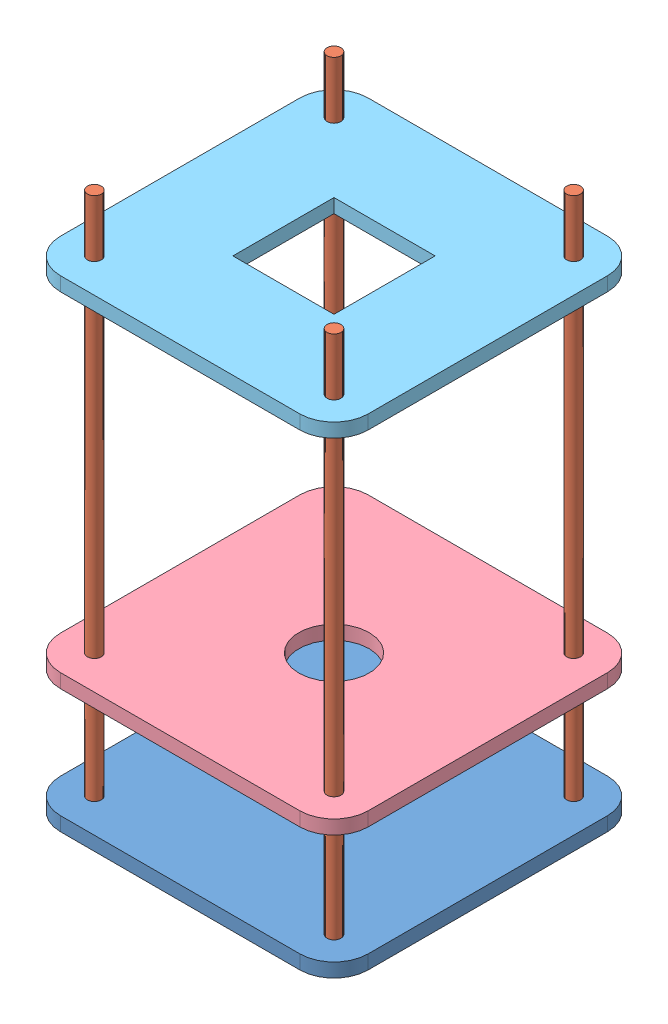
SolidWorks assembly ensanbblaje, configuration Predeterminado. Lengths in mm.
Overall size (280 500 280).
11 component instances, 5 part files, 16 mates.
Components (placement in the parent):
- base-2: base [Predeterminado] at (-174.1135 -97.9737 225.0155) size (280 12.7 280)
- VARILLA-2: VARILLA [Predeterminado] at (-283.1135 -107.9737 334.0155) x (0.715876 0 -0.698227) z (0.698227 0 0.715876) size (12.7 500 12.7)
- VARILLA-3: VARILLA [Predeterminado] at (-283.1135 -107.9737 116.0155) size (12.7 500 12.7)
- VARILLA-4: VARILLA [Predeterminado] at (-65.1135 -107.9737 334.0155) size (12.7 500 12.7)
- VARILLA-5: VARILLA [Predeterminado] at (-65.1135 -107.9737 116.0155) size (12.7 500 12.7)
- tuerca-1: tuerca [Predeterminado] at (-65.1135 -107.9737 116.0155) size (32.26 10 25.4)
- tuerca-2: tuerca [Predeterminado] at (-283.1135 -107.9737 334.0155) size (32.26 10 25.4)
- tuerca-3: tuerca [Predeterminado] at (-283.1135 -107.9737 116.0155) size (32.26 10 25.4)
- tuerca-4: tuerca [Predeterminado] at (-65.1135 -107.9737 334.0155) size (32.26 10 25.4)
- medio-1: medio [Predeterminado] at (-174.1135 14.7263 225.0155) size (280 12.7 280)
- tetcho-1: tetcho [Predeterminado] at (-174.1135 327.4263 225.0155) size (280 12.7 280)
Mates (geometry in assembly coordinates):
- Concéntrica1: concentric: cylinder of base-2 through (-283.1135 -97.9737 334.0155) axis (0 1 0) radius 6.35; cylinder of VARILLA-2 through (-283.1135 392.0263 334.0155) axis (0 -1 0) radius 6.35
- Concéntrica2: concentric: cylinder of base-2 through (-65.1135 -97.9737 334.0155) axis (0 1 0) radius 6.35; cylinder of VARILLA-4 through (-65.1135 392.0263 334.0155) axis (0 -1 0) radius 6.35
- Concéntrica3: concentric: cylinder of base-2 through (-283.1135 -97.9737 116.0155) axis (0 1 0) radius 6.35; cylinder of VARILLA-3 through (-283.1135 392.0263 116.0155) axis (0 -1 0) radius 6.35
- Coincidente3: coincident: circle of VARILLA-3; circle of tuerca-3
- Coincidente4: coincident: plane of base-2 through (-283.1135 -97.9737 334.0155) normal (0 -1 0); plane of tuerca-3 through (-283.1135 -97.9737 116.0155) normal (0 1 0)
- Coincidente5: coincident: circle of VARILLA-5; circle of tuerca-1
- Coincidente6: coincident: plane of base-2 through (-283.1135 -97.9737 334.0155) normal (0 -1 0); plane of tuerca-1 through (-65.1135 -97.9737 116.0155) normal (0 1 0)
- Coincidente7: coincident: circle of VARILLA-4; circle of tuerca-4
- Coincidente8: coincident: plane of base-2 through (-283.1135 -97.9737 334.0155) normal (0 -1 0); plane of tuerca-4 through (-65.1135 -97.9737 334.0155) normal (0 1 0)
- Coincidente9: coincident: circle of VARILLA-2; circle of tuerca-2
- Coincidente10: coincident: plane of base-2 through (-283.1135 -97.9737 334.0155) normal (0 -1 0); plane of tuerca-2 through (-283.1135 -97.9737 334.0155) normal (0 1 0)
- Concéntrica4: concentric: cylinder of VARILLA-2 through (-283.1135 392.0263 334.0155) axis (0 -1 0) radius 6.35; cylinder of medio-1 through (-283.1135 27.4263 334.0155) axis (0 -1 0) radius 6.35
- Concéntrica5: concentric: cylinder of VARILLA-5 through (-65.1135 392.0263 116.0155) axis (0 -1 0) radius 6.35; cylinder of medio-1 through (-65.1135 27.4263 116.0155) axis (0 -1 0) radius 6.35
- Distancia1: distance = 100 mm: plane of base-2 through (-283.1135 -85.2737 334.0155) normal (0 1 0); plane of medio-1 through (-65.1135 14.7263 334.0155) normal (0 -1 0)
- Concéntrica6: concentric: cylinder of VARILLA-4 through (-65.1135 392.0263 334.0155) axis (0 -1 0) radius 6.35; cylinder of tetcho-1 through (-65.1135 340.1263 334.0155) axis (0 -1 0) radius 6.35
- Distancia2: distance = 300 mm: plane of tetcho-1 through (-283.1135 327.4263 334.0155) normal (0 -1 0); plane of medio-1 through (-65.1135 27.4263 334.0155) normal (0 1 0)
